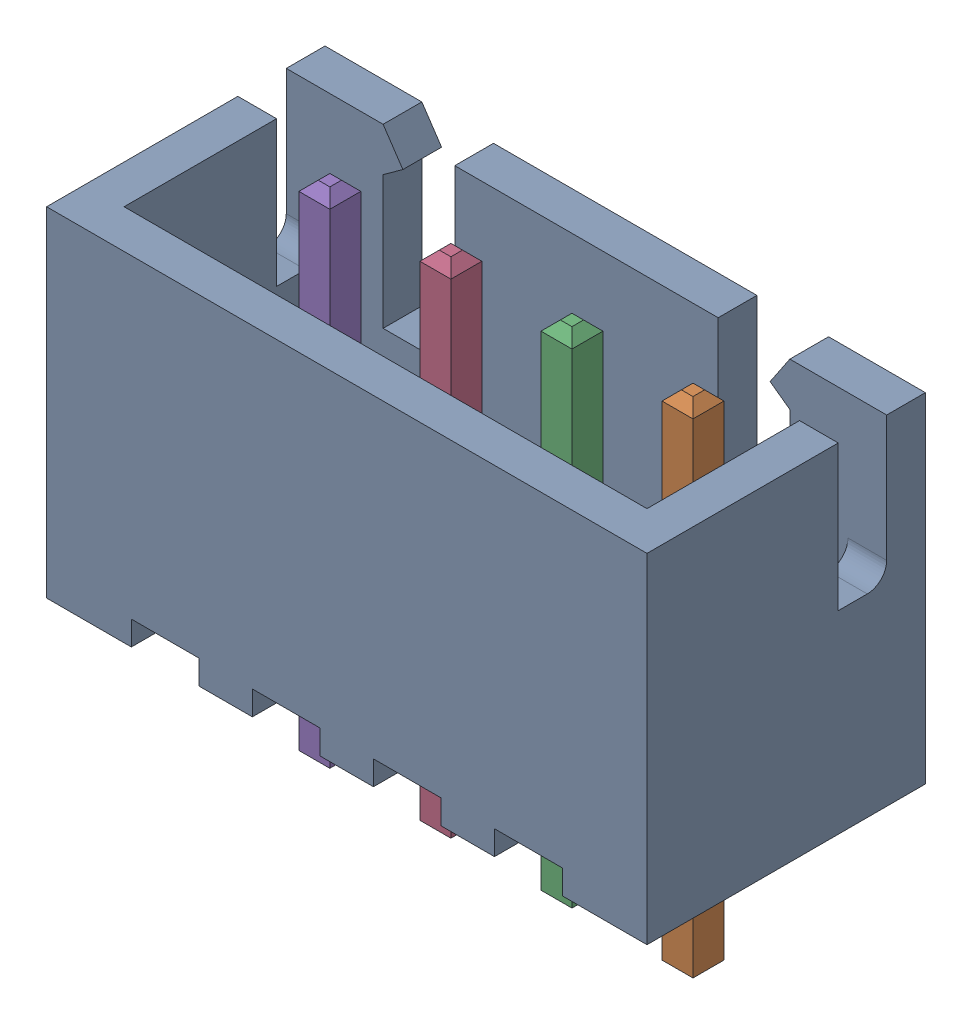
SolidWorks assembly 4 pin Header, configuration 4 pin Header. Lengths in mm.
Overall size (12.4 10.4 5.75).
5 component instances, 2 part files, 0 mates.
Components (placement in the parent):
- B4B-XH-A (BODY)-1: B4B-XH-A (BODY) [B4B-XH-A (BODY)] at (1.9192 5.3562 13.8157) size (12.4 7 5.75)
- B4B-XH-A (PIN)-1: B4B-XH-A (PIN) [B4B-XH-A (PIN)] at (5.6692 12.3562 13.2907) x (-1 0 0) z (0 0 1) size (0.64 10.4 0.64)
- B4B-XH-A (PIN)-2: B4B-XH-A (PIN) [B4B-XH-A (PIN)] at (3.1692 12.3562 13.2907) x (-1 0 0) z (0 0 1) size (0.64 10.4 0.64)
- B4B-XH-A (PIN)-3: B4B-XH-A (PIN) [B4B-XH-A (PIN)] at (0.6692 12.3562 13.2907) x (-1 0 0) z (0 0 1) size (0.64 10.4 0.64)
- B4B-XH-A (PIN)-4: B4B-XH-A (PIN) [B4B-XH-A (PIN)] at (-1.8308 12.3562 13.2907) x (-1 0 0) z (0 0 1) size (0.64 10.4 0.64)
